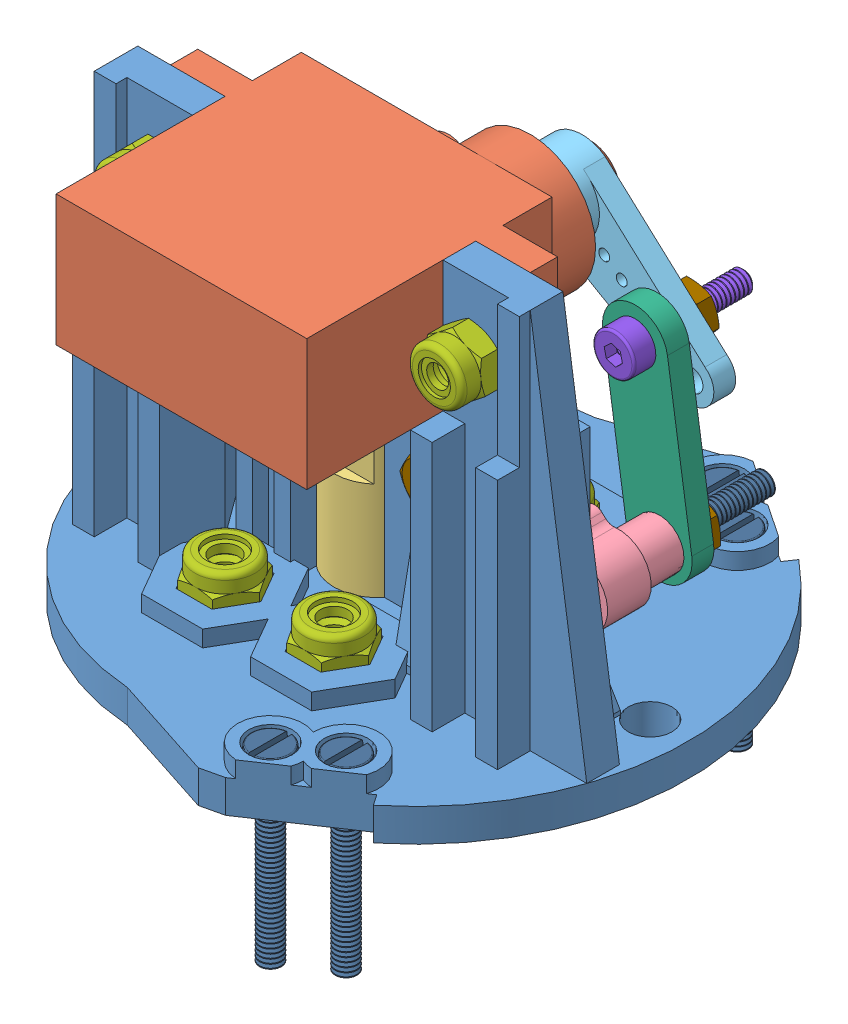
SolidWorks assembly Rückseite, configuration Standard. Lengths in mm.
Overall size (50 51 49.14).
25 component instances, 11 part files, 54 mates.
Components (placement in the parent):
- Backside-1: Backside [Standard] at (-0.7502 -6.4244 50) size (50 38 49.14)
- servo-1: servo [Standard] at (-9.7502 31.5756 70.5) x (1 0 0) z (0 1 0) size (33 29.25 12)
- Drücker-1: Drücker [Standard] at (-2.5879 13.5929 78.2478) x (1 0 0) z (0 0 -1) size (8 29 8)
- Hebel-1: Hebel [Standard] at (9.2498 10.5756 51) x (0.998665 -0.051659 0) z (0 0 -1) size (30.92 10.86 7.75)
- Servo-Arm-1: Servo-Arm [Standard] at (7.2498 25.5756 39.25) x (0.806683 -0.590985 0) z (-0.590985 -0.806683 0) size (20.6 4.3 7.2)
- Hebel2-1: Hebel2 [Standard] at (18.3545 4.2417 41.25) x (-0.148742 0.988876 0) z (0.988876 0.148742 0) size (21 2 6)
- User Library-Mutter DIN-985_-1: User Library-Mutter DIN-985_ [Mutter DIN-985 M3-A2] at (-4.7502 -3.4244 60) x (0 1 0) z (0 0 1) size (4 6.35 5.5)
- User Library-Mutter DIN-985_-2: User Library-Mutter DIN-985_ [Mutter DIN-985 M3-A2] at (5.2498 -3.4244 60) x (0 1 0) z (-0.866025 0 0.5) size (4 6.35 5.5)
- User Library-Mutter DIN-985_-3: User Library-Mutter DIN-985_ [Mutter DIN-985 M3-A2] at (5.2498 -3.4244 40) x (0 1 0) z (-0.866025 0 -0.5) size (4 6.35 5.5)
- User Library-Mutter DIN-985_-4: User Library-Mutter DIN-985_ [Mutter DIN-985 M3-A2] at (-4.7502 -3.4244 40) x (0 1 0) z (-0.866025 0 0.5) size (4 6.35 5.5)
- socket head cap screw 4762_din-1: socket head cap screw 4762_din [ISO 4762 M2 x 10 --- 10S] at (9.2498 10.5756 43.8) x (0 0 1) z (0.035285 -0.999377 0) size (12 3.8 3.8)
- socket head cap screw 4762_din-2: socket head cap screw 4762_din [ISO 4762 M2 x 10 --- 10S] at (-0.7502 11.0929 55) x (0 0 -1) z (0.999211 -0.039713 0) size (12 3.8 3.8)
- socket head cap screw 4762_din-3: socket head cap screw 4762_din [ISO 4762 M2 x 10 --- 10S] at (16.1233 19.0748 45.25) x (0 0 -1) z (-0.686907 0.726745 0) size (12 3.8 3.8)
- nut__style_1__m2x0_4__ansi_b18_2_4_1m-1: nut__style_1__m2x0_4__ansi_b18_2_4_1m [Default] at (-0.7502 11.0929 47) x (0.997705 -0.067711 0) z (0 0 -1) size (4.62 4 1.6)
- nut__style_1__m2x0_4__ansi_b18_2_4_1m-2: nut__style_1__m2x0_4__ansi_b18_2_4_1m [Default] at (16.1233 19.0748 37.65) x (0.980747 -0.195284 0) z (0 0 1) size (4.62 4 1.6)
- nut__style_1__m2x0_4__ansi_b18_2_4_1m-3: nut__style_1__m2x0_4__ansi_b18_2_4_1m [Default] at (9.2498 10.5756 54.2) x (0.532315 -0.846547 0) z (0 0 1) size (4.62 4 1.6)
- User Library-Mutter DIN-985_-5: User Library-Mutter DIN-985_ [Mutter DIN-985 M2,5-A2] at (-12.7502 25.5756 58) x (0 0 1) z (0.965495 0.260421 0) size (3.8 5.77 5)
- User Library-Mutter DIN-985_-6: User Library-Mutter DIN-985_ [Mutter DIN-985 M2,5-A2] at (16.2498 25.5756 58) x (0 0 1) z (-0.395566 -0.918438 0) size (3.8 5.77 5)
- slotted cheese head screw_din-1: slotted cheese head screw_din [ISO 1207 - M2 x 16 --- 16S] at (10.151 -2.0244 70.7313) x (0 -1 0) z (0 0 1) size (17.4 3.8 3.8)
- slotted cheese head screw_din-2: slotted cheese head screw_din [ISO 1207 - M2 x 16 --- 16S] at (10.151 -2.0244 29.2687) x (0 -1 0) z (0 0 1) size (17.4 3.8 3.8)
- slotted cheese head screw_din-3: slotted cheese head screw_din [ISO 1207 - M2 x 16 --- 16S] at (14.3028 -2.0244 32.0549) x (0 -1 0) z (0 0 1) size (17.4 3.8 3.8)
- slotted cheese head screw_din-4: slotted cheese head screw_din [ISO 1207 - M2 x 16 --- 16S] at (14.3028 -2.0244 67.9451) x (0 -1 0) z (0 0 1) size (17.4 3.8 3.8)
- slotted cheese head screw_din-5: slotted cheese head screw_din [ISO 1207 - M2 x 16 --- 16S] at (18.3545 4.2417 50.85) x (0 0 -1) z (1 0 0) size (17.4 3.8 3.8)
- nut__style_1__m2x0_4__ansi_b18_2_4_1m-4: nut__style_1__m2x0_4__ansi_b18_2_4_1m [Default] at (18.3545 4.2417 41.25) x (0.924405 -0.381413 0) z (0 0 -1) size (4.62 4 1.6)
- cross fh tapping 7976_din-2: cross fh tapping 7976_din [Tapping screw DIN 7982-ST2.9x6.5-C-Z-S] at (7.2498 25.5756 38.5) x (0 0 1) z (-1 0 0) size (6.51 5.5 5.5)
Mates (geometry in assembly coordinates):
- Konzentrisch1: concentric anti-aligned: cylinder of Drücker-1 through (-0.7502 -15.4071 50) axis (0 1 0) radius 4; cylinder of Backside-1 through (-0.7502 -3.4244 50) axis (0 -1 0) radius 4
- Konzentrisch2: concentric aligned: cylinder of Backside-1 through (9.2498 10.5756 57.5) axis (0 0 1) radius 1.15; cylinder of Hebel-1 through (9.2498 10.5756 49) axis (0 0 1) radius 1.15
- Deckungsgleich1: coincident anti-aligned: plane of Hebel-1 through (9.2498 10.5756 49) normal (0 0 -1); plane of Backside-1 through (6.7498 13.5756 49) normal (0 0 1)
- Parallel1: parallel anti-aligned: plane of Drücker-1 through (-5.7502 5.5929 51) normal (0 0 -1); plane of Hebel-1 through (9.2498 10.5756 51) normal (0 0 1)
- Langloch1: slot anti-aligned: cylinder of Drücker-1 through (-0.7502 11.0929 54) axis (0 0 -1) radius 1; plane of Hebel-1 through (9.3092 11.7241 49) normal (-0.051659 -0.998665 0); cylinder of Hebel-1 through (-6.7288 11.4022 49) axis (0 0 1) radius 1.15
- Konzentrisch3: concentric anti-aligned: cylinder of servo-1 through (7.2498 25.5756 44) axis (0 0 1) radius 6; cylinder of Servo-Arm-1 through (7.2498 25.5756 43.55) axis (0 0 -1) radius 2.25
- Deckungsgleich6: coincident anti-aligned: plane of Backside-1 through (-9.7502 31.5756 58) normal (1 0 0); plane of servo-1 through (-9.7502 31.5756 48) normal (-1 0 0)
- Deckungsgleich7: coincident anti-aligned: plane of servo-1 through (18.2498 31.5756 55) normal (0 0 1); plane of Backside-1 through (-17.7502 19.5756 55) normal (0 0 -1)
- Deckungsgleich11: coincident aligned: plane of Backside-1 through (-0.7502 31.5756 50) normal (0 1 0); plane of servo-1 through (-9.7502 31.5756 48) normal (0 1 0)
- Deckungsgleich9: coincident anti-aligned: plane of Hebel2-1 through (18.3545 4.2417 41.25) normal (0 0 -1); plane of Servo-Arm-1 through (7.2498 25.5756 41.25) normal (0 0 1)
- Konzentrisch4: concentric anti-aligned: cylinder of Hebel-1 through (18.3545 4.2417 47) axis (0 0 1) radius 1.15; cylinder of Hebel2-1 through (18.3545 4.2417 43.25) axis (0 0 -1) radius 1.15
- Deckungsgleich12: coincident anti-aligned: plane of servo-1 through (7.2498 25.5756 41.25) normal (0 0 -1); plane of Servo-Arm-1 through (7.2498 25.5756 41.25) normal (0 0 1)
- Konzentrisch5: concentric aligned: cylinder of Servo-Arm-1 through (16.1233 19.0748 41.25) axis (0 0 -1) radius 0.5; cylinder of Hebel2-1 through (16.1233 19.0748 43.25) axis (0 0 -1) radius 1.15
- Deckungsgleich28: coincident anti-aligned: plane of Backside-1 through (-0.7502 -3.4244 50) normal (0 1 0); plane of User Library-Mutter DIN-985_-1 through (-7.4789 -3.4244 60) normal (0 -1 0)
- Deckungsgleich29: coincident anti-aligned: plane of Backside-1 through (-0.7502 -3.4244 50) normal (0 1 0); plane of User Library-Mutter DIN-985_-2 through (3.8855 -3.4244 57.6369) normal (0 -1 0)
- Deckungsgleich31: coincident anti-aligned: plane of Backside-1 through (-0.7502 -3.4244 50) normal (0 1 0); plane of User Library-Mutter DIN-985_-3 through (6.6142 -3.4244 37.6369) normal (0 -1 0)
- Deckungsgleich30: coincident anti-aligned: plane of Backside-1 through (-0.7502 -3.4244 50) normal (0 1 0); plane of User Library-Mutter DIN-985_-4 through (-6.1145 -3.4244 37.6369) normal (0 -1 0)
- Deckungsgleich21: coincident anti-aligned: plane of Backside-1 through (9.2498 10.5756 45.8) normal (0 0 -1); plane of socket head cap screw 4762_din-1 through (7.351 10.5086 45.8) normal (0 0 1)
- Konzentrisch20: concentric anti-aligned: cylinder of Backside-1 through (9.2498 10.5756 57.5) axis (0 0 1) radius 1.15; cylinder of socket head cap screw 4762_din-1 through (9.2498 10.5756 12.05) axis (0 0 -1) radius 1
- Konzentrisch19: concentric anti-aligned: cylinder of Drücker-1 through (-0.7502 11.0929 54) axis (0 0 -1) radius 1; cylinder of socket head cap screw 4762_din-2 through (-0.7502 11.0929 86.75) axis (0 0 1) radius 1
- Deckungsgleich38: coincident anti-aligned: plane of Hebel2-1 through (18.3545 4.2417 43.25) normal (0 0 1); plane of socket head cap screw 4762_din-3 through (14.7425 17.7697 43.25) normal (0 0 -1)
- Konzentrisch38: concentric anti-aligned: cylinder of Hebel2-1 through (16.1233 19.0748 43.25) axis (0 0 -1) radius 1.15; cylinder of socket head cap screw 4762_din-3 through (16.1233 19.0748 77) axis (0 0 1) radius 1
- Deckungsgleich41: coincident anti-aligned: plane of Drücker-1 through (4.2498 5.5929 47) normal (0 0 -1); plane of nut__style_1__m2x0_4__ansi_b18_2_4_1m-1 through (1.5545 10.9365 47) normal (0 0 1)
- Konzentrisch49: concentric aligned: circle of socket head cap screw 4762_din-2; circle of nut__style_1__m2x0_4__ansi_b18_2_4_1m-1
- Deckungsgleich39: coincident anti-aligned: plane of Servo-Arm-1 through (7.2498 25.5756 39.25) normal (0 0 -1); plane of nut__style_1__m2x0_4__ansi_b18_2_4_1m-2 through (18.3889 18.6237 39.25) normal (0 0 1)
- Konzentrisch50: concentric anti-aligned: circle of socket head cap screw 4762_din-3; circle of nut__style_1__m2x0_4__ansi_b18_2_4_1m-2
- Deckungsgleich33: coincident anti-aligned: plane of Backside-1 through (9.2498 10.5756 54.2) normal (0 0 1); plane of nut__style_1__m2x0_4__ansi_b18_2_4_1m-3 through (10.4795 8.6201 54.2) normal (0 0 -1)
- Konzentrisch48: concentric aligned: circle of socket head cap screw 4762_din-1; circle of nut__style_1__m2x0_4__ansi_b18_2_4_1m-3
- Deckungsgleich36: coincident anti-aligned: plane of Backside-1 through (-11.7502 31.5756 58) normal (0 0 1); plane of User Library-Mutter DIN-985_-5 through (-12.1447 23.3307 58) normal (0 0 -1)
- Deckungsgleich37: coincident anti-aligned: plane of Backside-1 through (15.2498 31.5756 58) normal (0 0 1); plane of User Library-Mutter DIN-985_-6 through (14.1143 26.4954 58) normal (0 0 -1)
- Konzentrisch51: concentric aligned: circle of Backside-1; circle of User Library-Mutter DIN-985_-1
- Konzentrisch52: concentric aligned: circle of Backside-1; circle of User Library-Mutter DIN-985_-2
- Konzentrisch53: concentric aligned: circle of Backside-1; circle of User Library-Mutter DIN-985_-4
- Konzentrisch54: concentric aligned: circle of Backside-1; circle of User Library-Mutter DIN-985_-3
- Konzentrisch55: concentric aligned: circle of User Library-Mutter DIN-985_-5; cylinder of Backside-1 through (-12.7502 25.5756 41) axis (0 0 1) radius 1.25
- Konzentrisch56: concentric aligned: circle of User Library-Mutter DIN-985_-6; cylinder of Backside-1 through (16.2498 25.5756 41) axis (0 0 1) radius 1.25
- Deckungsgleich40: coincident anti-aligned: plane of Drücker-1 through (4.2498 5.5929 53) normal (0 0 1); plane of socket head cap screw 4762_din-2 through (-0.6747 12.9914 53) normal (0 0 -1)
- Konzentrisch59: concentric aligned: cylinder of Backside-1 through (14.3028 -13.4244 32.0549) axis (0 1 0) radius 1.1; cylinder of slotted cheese head screw_din-3 through (14.3028 23.3756 32.0549) axis (0 1 0) radius 1
- Konzentrisch60: concentric aligned: cylinder of Backside-1 through (10.151 -13.4244 29.2687) axis (0 1 0) radius 1.1; cylinder of slotted cheese head screw_din-2 through (10.151 23.3756 29.2687) axis (0 1 0) radius 1
- Konzentrisch61: concentric aligned: cylinder of Backside-1 through (14.3028 -13.4244 67.9451) axis (0 1 0) radius 1.1; cylinder of slotted cheese head screw_din-4 through (14.3028 23.3756 67.9451) axis (0 1 0) radius 1
- Konzentrisch62: concentric aligned: cylinder of Backside-1 through (10.151 -13.4244 70.7313) axis (0 1 0) radius 1.1; cylinder of slotted cheese head screw_din-1 through (10.151 23.3756 70.7313) axis (0 1 0) radius 1
- Deckungsgleich42: coincident anti-aligned: plane of Backside-1 through (-0.7502 -3.4244 50) normal (0 1 0); plane of slotted cheese head screw_din-3 through (15.3028 -3.4244 32.0549) normal (0 -1 0)
- Deckungsgleich43: coincident anti-aligned: plane of Backside-1 through (-0.7502 -3.4244 50) normal (0 1 0); plane of slotted cheese head screw_din-2 through (11.151 -3.4244 29.2687) normal (0 -1 0)
- Deckungsgleich44: coincident anti-aligned: plane of Backside-1 through (-0.7502 -3.4244 50) normal (0 1 0); plane of slotted cheese head screw_din-1 through (11.151 -3.4244 70.7313) normal (0 -1 0)
- Deckungsgleich45: coincident anti-aligned: plane of Backside-1 through (-0.7502 -3.4244 50) normal (0 1 0); plane of slotted cheese head screw_din-4 through (15.3028 -3.4244 67.9451) normal (0 -1 0)
- Konzentrisch64: concentric aligned: cylinder of Hebel-1 through (18.3545 4.2417 47) axis (0 0 1) radius 1.15; cylinder of slotted cheese head screw_din-5 through (18.3545 4.2417 76.25) axis (0 0 1) radius 1
- Deckungsgleich47: coincident aligned: circle of Hebel-1; plane of slotted cheese head screw_din-5 through (18.3545 5.2417 49.45) normal (0 0 -1)
- Deckungsgleich48: coincident anti-aligned: plane of Hebel2-1 through (18.3545 4.2417 41.25) normal (0 0 -1); plane of nut__style_1__m2x0_4__ansi_b18_2_4_1m-4 through (20.4898 3.3606 41.25) normal (0 0 1)
- Konzentrisch65: concentric anti-aligned: cylinder of Hebel2-1 through (18.3545 4.2417 43.25) axis (0 0 -1) radius 1.15; cylinder of nut__style_1__m2x0_4__ansi_b18_2_4_1m-4 through (18.3545 4.2417 41.25) axis (0 0 1) radius 0.7835
- Deckungsgleich50: coincident: circle of Servo-Arm-1; cone of cross fh tapping 7976_din-2 through (7.2498 25.5756 40.2) axis (0 0 1)
- Parallel2: parallel anti-aligned: plane of Backside-1 through (8.5407 -1.9244 40) normal (-0.866025 0 0.5); plane of User Library-Mutter DIN-985_-3 through (8.4252 0.5766 40) normal (0.866025 0 -0.5)
- Parallel3: parallel anti-aligned: plane of Backside-1 through (-1.4593 -1.9244 40) normal (-0.866025 0 0.5); plane of User Library-Mutter DIN-985_-4 through (-1.5748 0.5766 40) normal (0.866025 0 -0.5)
- Parallel4: parallel anti-aligned: plane of Backside-1 through (-3.1047 -1.9244 62.85) normal (-0.866025 0 -0.5); plane of User Library-Mutter DIN-985_-1 through (-3.1625 0.5766 62.75) normal (0.866025 0 0.5)
- Parallel5: parallel anti-aligned: plane of Backside-1 through (6.8953 -1.9244 62.85) normal (-0.866025 0 -0.5); plane of User Library-Mutter DIN-985_-2 through (6.8375 0.5766 62.75) normal (0.866025 0 0.5)
